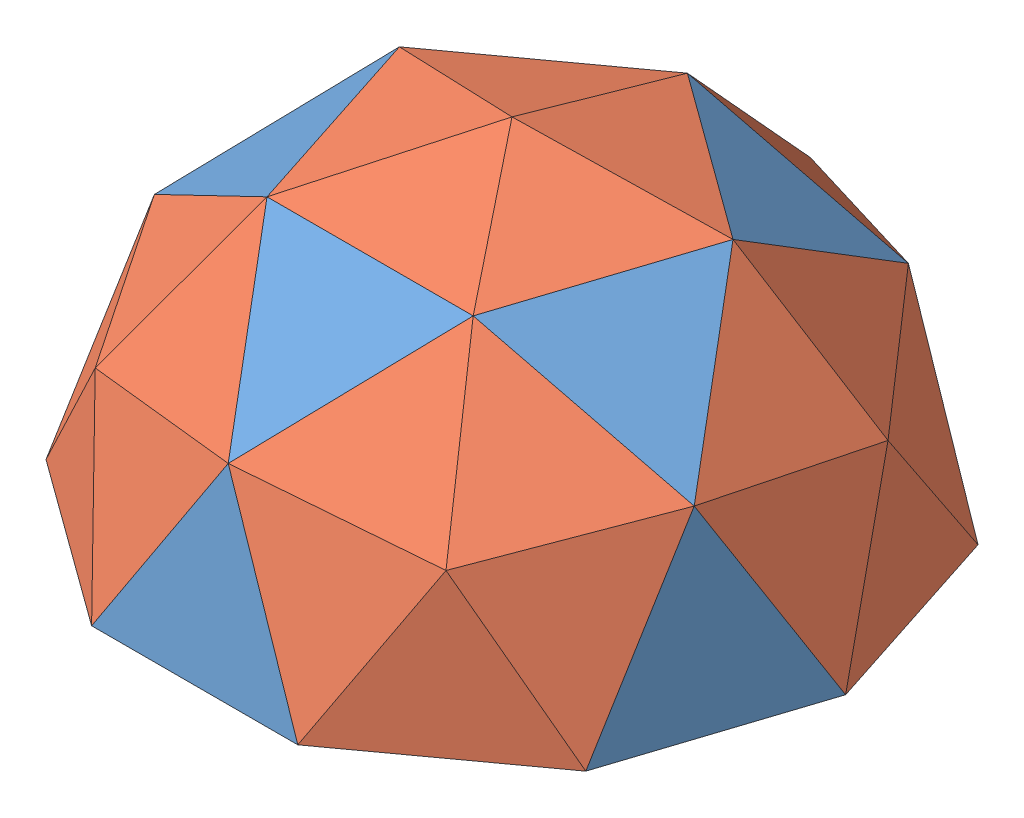
SolidWorks assembly geodome_2V_assembly, configuration Default. Lengths in mm.
Overall size (6090.08 6762.26 6173.15).
40 component instances, 2 part files, 27 mates.
Components (placement in the parent):
- BBB^geodome_2V_assembly_sketch-1: BBB^geodome_2V_assembly_sketch [Default] at (2618.034 525.7311 850.6508) x (0.29759 0.059759 -0.952822) z (0.934172 0.187592 0.303531) size (1850.67 1659.13 10) (virtual)
- BBB^geodome_2V_assembly_sketch-2: BBB^geodome_2V_assembly_sketch [Default] at (1618.034 525.7311 -2227.0327) x (-0.814227 0.059759 -0.577463) z (0.57735 0.187592 -0.794654) size (1850.67 1659.13 10) (virtual)
- BBB^geodome_2V_assembly_sketch-3: BBB^geodome_2V_assembly_sketch [Default] at (-1618.034 525.7311 -2227.0327) x (-0.80081 0.059759 0.59593) z (-0.57735 0.187592 -0.794654) size (1850.67 1659.13 10) (virtual)
- BBB^geodome_2V_assembly_sketch-4: BBB^geodome_2V_assembly_sketch [Default] at (-2618.034 525.7311 850.6508) x (0.319299 0.059759 0.945768) z (-0.934172 0.187592 0.303531) size (1850.67 1659.13 10) (virtual)
- BBB^geodome_2V_assembly_sketch-5: BBB^geodome_2V_assembly_sketch [Default] at (0 525.7311 2752.7638) x (0.998148 0.059759 -0.011413) z (0 0.187592 0.982247) size (1850.67 1659.13 10) (virtual)
- AAB^geodome_2V_assembly_sketch-10: AAB^geodome_2V_assembly_sketch [Default] at (551.221 2670.7024 -758.6906) x (-0.980855 0.187327 -0.053216) z (-0.194739 -0.943522 0.268035) size (1529.28 1639.6 10) (virtual)
- AAB^geodome_2V_assembly_sketch-11: AAB^geodome_2V_assembly_sketch [Default] at (-551.221 2670.7024 -758.6906) x (-0.353712 0.187327 0.916404) z (0.194739 -0.943522 0.268035) size (1529.28 1639.6 10) (virtual)
- AAB^geodome_2V_assembly_sketch-12: AAB^geodome_2V_assembly_sketch [Default] at (-891.8943 2670.7024 289.794) x (0.762249 0.187327 0.619584) z (0.315094 -0.943522 -0.10238) size (1529.28 1639.6 10) (virtual)
- AAB^geodome_2V_assembly_sketch-13: AAB^geodome_2V_assembly_sketch [Default] at (0 2670.7024 937.7931) x (0.824808 0.187327 -0.53348) z (0 -0.943522 -0.331309) size (1529.28 1639.6 10) (virtual)
- AAB^geodome_2V_assembly_sketch-14: AAB^geodome_2V_assembly_sketch [Default] at (891.8943 2670.7024 289.794) x (-0.25249 0.187327 -0.949293) z (-0.315094 -0.943522 -0.10238) size (1529.28 1639.6 10) (virtual)
- BBB^geodome_2V_assembly_sketch-6: BBB^geodome_2V_assembly_sketch [Default] at (1618.034 2227.0327 525.7311) x (0.80081 -0.506291 -0.319958) z (0.57735 0.794654 0.187592) size (1850.67 1659.13 10) (virtual)
- AAB^geodome_2V_assembly_sketch-15: AAB^geodome_2V_assembly_sketch [Default] at (2670.7024 355.5867 -867.7638) x (-0.322433 0.560934 -0.76249) z (-0.943522 -0.125624 0.306569) size (1529.28 1639.6 10) (virtual)
- AAB^geodome_2V_assembly_sketch-16: AAB^geodome_2V_assembly_sketch [Default] at (2670.7024 935.1748 70.0293) x (0.187327 -0.470398 -0.862342) z (-0.943522 -0.330384 -0.02474) size (1529.28 1639.6 10) (virtual)
- AAB^geodome_2V_assembly_sketch-18: AAB^geodome_2V_assembly_sketch [Default] at (2119.4814 1872.9679 -109.0732) x (0.658423 -0.735882 0.15798) z (-0.748783 -0.661694 0.038534) size (1529.28 1639.6 10) (virtual)
- AAB^geodome_2V_assembly_sketch-19: AAB^geodome_2V_assembly_sketch [Default] at (1778.8081 1872.9679 -1157.5578) x (0.439817 0.131372 0.888427) z (-0.628428 -0.661694 0.408949) size (1529.28 1639.6 10) (virtual)
- AAB^geodome_2V_assembly_sketch-20: AAB^geodome_2V_assembly_sketch [Default] at (2119.4814 935.1748 -1626.4544) x (-0.166385 0.932849 0.319545) z (-0.748783 -0.330384 0.574604) size (1529.28 1639.6 10) (virtual)
- BBB^geodome_2V_assembly_sketch-7: BBB^geodome_2V_assembly_sketch [Default] at (1000 2227.0327 -1376.3819) x (-0.056835 -0.506291 -0.860488) z (0.356822 0.794654 -0.491123) size (1850.67 1659.13 10) (virtual)
- BBB^geodome_2V_assembly_sketch-8: BBB^geodome_2V_assembly_sketch [Default] at (-1000 2227.0327 -1376.3819) x (-0.835936 -0.506291 -0.211852) z (-0.356822 0.794654 -0.491123) size (1850.67 1659.13 10) (virtual)
- BBB^geodome_2V_assembly_sketch-9: BBB^geodome_2V_assembly_sketch [Default] at (-1618.034 2227.0327 525.7311) x (-0.459802 -0.506291 0.729556) z (-0.57735 0.794654 0.187592) size (1850.67 1659.13 10) (virtual)
- BBB^geodome_2V_assembly_sketch-10: BBB^geodome_2V_assembly_sketch [Default] at (0 2227.0327 1701.3016) x (0.551762 -0.506291 0.662743) z (0 0.794654 0.607062) size (1850.67 1659.13 10) (virtual)
- AAB^geodome_2V_assembly_sketch-22: AAB^geodome_2V_assembly_sketch [Default] at (551.221 1872.9679 -2049.4521) x (0.353712 -0.735882 -0.577378) z (-0.194739 -0.661694 0.724043) size (1529.28 1639.6 10) (virtual)
- AAB^geodome_2V_assembly_sketch-23: AAB^geodome_2V_assembly_sketch [Default] at (-1778.8081 1872.9679 -1157.5578) x (-0.439817 -0.735882 -0.51482) z (0.628428 -0.661694 0.408949) size (1529.28 1639.6 10) (virtual)
- AAB^geodome_2V_assembly_sketch-24: AAB^geodome_2V_assembly_sketch [Default] at (-1650.5848 1872.9679 1334.042) x (-0.625534 -0.735882 0.259202) z (0.583129 -0.661694 -0.471299) size (1529.28 1639.6 10) (virtual)
- AAB^geodome_2V_assembly_sketch-25: AAB^geodome_2V_assembly_sketch [Default] at (758.6906 1872.9679 1982.0411) x (0.053216 -0.735882 0.675016) z (-0.268035 -0.661694 -0.700228) size (1529.28 1639.6 10) (virtual)
- AAB^geodome_2V_assembly_sketch-26: AAB^geodome_2V_assembly_sketch [Default] at (891.8943 935.1748 -2518.3486) x (-0.762249 -0.470398 -0.444637) z (-0.315094 -0.330384 0.889698) size (1529.28 1639.6 10) (virtual)
- AAB^geodome_2V_assembly_sketch-27: AAB^geodome_2V_assembly_sketch [Default] at (-2119.4814 935.1748 -1626.4544) x (-0.658423 -0.470398 0.587542) z (0.748783 -0.330384 0.574604) size (1529.28 1639.6 10) (virtual)
- AAB^geodome_2V_assembly_sketch-28: AAB^geodome_2V_assembly_sketch [Default] at (-2201.8058 935.1748 1513.1446) x (0.355322 -0.470398 0.807757) z (0.777868 -0.330384 -0.534573) size (1529.28 1639.6 10) (virtual)
- AAB^geodome_2V_assembly_sketch-29: AAB^geodome_2V_assembly_sketch [Default] at (758.6906 935.1748 2561.6291) x (0.878023 -0.470398 -0.08832) z (-0.268035 -0.330384 -0.904988) size (1529.28 1639.6 10) (virtual)
- AAB^geodome_2V_assembly_sketch-30: AAB^geodome_2V_assembly_sketch [Default] at (0 355.5867 -2808.1427) x (-0.824808 0.560934 0.071029) z (0 -0.125624 0.992078) size (1529.28 1639.6 10) (virtual)
- AAB^geodome_2V_assembly_sketch-31: AAB^geodome_2V_assembly_sketch [Default] at (-2670.7024 355.5867 -867.7638) x (-0.187327 0.560934 0.806388) z (0.943522 -0.125624 0.306569) size (1529.28 1639.6 10) (virtual)
- AAB^geodome_2V_assembly_sketch-32: AAB^geodome_2V_assembly_sketch [Default] at (-1650.5848 355.5867 2271.8351) x (0.709034 0.560934 0.427346) z (0.583129 -0.125624 -0.802608) size (1529.28 1639.6 10) (virtual)
- AAB^geodome_2V_assembly_sketch-33: AAB^geodome_2V_assembly_sketch [Default] at (1650.5848 355.5867 2271.8351) x (0.625534 0.560934 -0.542274) z (-0.583129 -0.125624 -0.802608) size (1529.28 1639.6 10) (virtual)
- AAB^geodome_2V_assembly_sketch-34: AAB^geodome_2V_assembly_sketch [Default] at (-891.8943 935.1748 -2518.3486) x (0.25249 0.932849 0.256987) z (0.315094 -0.330384 0.889698) size (1529.28 1639.6 10) (virtual)
- AAB^geodome_2V_assembly_sketch-35: AAB^geodome_2V_assembly_sketch [Default] at (-2670.7024 935.1748 70.0293) x (0.322433 0.932849 -0.160719) z (0.943522 -0.330384 -0.02474) size (1529.28 1639.6 10) (virtual)
- AAB^geodome_2V_assembly_sketch-36: AAB^geodome_2V_assembly_sketch [Default] at (-758.6906 935.1748 2561.6291) x (-0.053216 0.932849 -0.356316) z (0.268035 -0.330384 -0.904988) size (1529.28 1639.6 10) (virtual)
- AAB^geodome_2V_assembly_sketch-37: AAB^geodome_2V_assembly_sketch [Default] at (2201.8058 935.1748 1513.1446) x (-0.355322 0.932849 -0.059497) z (-0.777868 -0.330384 -0.534573) size (1529.28 1639.6 10) (virtual)
- AAB^geodome_2V_assembly_sketch-38: AAB^geodome_2V_assembly_sketch [Default] at (-551.221 1872.9679 -2049.4521) x (0.980855 0.131372 -0.143751) z (0.194739 -0.661694 0.724043) size (1529.28 1639.6 10) (virtual)
- AAB^geodome_2V_assembly_sketch-39: AAB^geodome_2V_assembly_sketch [Default] at (-2119.4814 1872.9679 -109.0732) x (0.166385 0.131372 -0.97727) z (0.748783 -0.661694 0.038534) size (1529.28 1639.6 10) (virtual)
- AAB^geodome_2V_assembly_sketch-40: AAB^geodome_2V_assembly_sketch [Default] at (-758.6906 1872.9679 1982.0411) x (-0.878023 0.131372 -0.460235) z (0.268035 -0.661694 -0.700228) size (1529.28 1639.6 10) (virtual)
- AAB^geodome_2V_assembly_sketch-41: AAB^geodome_2V_assembly_sketch [Default] at (1650.5848 1872.9679 1334.042) x (-0.709034 0.131372 0.692829) z (-0.583129 -0.661694 -0.471299) size (1529.28 1639.6 10) (virtual)
Mates (geometry in assembly coordinates):
- InPlace1: in place: plane of BBB^geodome_2V_assembly_sketch-1 through (2618.034 525.7311 850.6508) normal (0.934172 0.187592 0.303531); moOrthogonalPlaneRef_w of BBB^geodome_2V_assembly_sketch-1 through (2618.034 525.7311 850.6508) normal (-0.196881 0.980427 0); plane of BBB^geodome_2V_assembly_sketch-1 through (2618.034 525.7311 850.6508) normal (0.29759 0.059759 -0.952822); unknown of BBB^geodome_2V_assembly_sketch-1
- Coincident1: coincident: plane of assembly; plane of ?; plane of assembly
- Coincident2: coincident: plane of BBB^geodome_2V_assembly_sketch-1 through (2618.034 525.7311 850.6508) normal (-0.196881 0.980427 0)
- Coincident3: coincident: plane of BBB^geodome_2V_assembly_sketch-1 through (2618.034 525.7311 850.6508) normal (0.29759 0.059759 -0.952822)
- InPlace2: in place: plane of AAB^geodome_2V_assembly_sketch-10 through (551.221 2670.7024 -758.6906) normal (-0.194739 -0.943522 0.268035); plane of AAB^geodome_2V_assembly_sketch-10 through (551.221 2670.7024 -758.6906) normal (0 -0.273267 -0.961938); plane of AAB^geodome_2V_assembly_sketch-10 through (551.221 2670.7024 -758.6906) normal (-0.980855 0.187327 -0.053216); unknown of AAB^geodome_2V_assembly_sketch-10
- Coincident4: coincident: plane of assembly; plane of ?; plane of assembly
- Coincident5: coincident: plane of AAB^geodome_2V_assembly_sketch-10 through (551.221 2670.7024 -758.6906) normal (0 -0.273267 -0.961938)
- Coincident6: coincident: plane of AAB^geodome_2V_assembly_sketch-10 through (551.221 2670.7024 -758.6906) normal (-0.980855 0.187327 -0.053216)
- Coincident7: coincident: unknown of BBB^geodome_2V_assembly_sketch-1; unknown of BBB^geodome_2V_assembly_sketch-6
- Coincident8: coincident: line of BBB^geodome_2V_assembly_sketch-6 through (2427.051 1577.1933 788.5967) axis (-0.5 0.525731 -0.688191)
- Coincident9: coincident: line of AAB^geodome_2V_assembly_sketch-14 through (1500 2551.9524 -487.3795) axis (-0.309017 0 0.951057); line of BBB^geodome_2V_assembly_sketch-6 through (1500 2551.9524 -487.3795) axis (-0.309017 0 0.951057)
- Coincident10: coincident: unknown of AAB^geodome_2V_assembly_sketch-15; unknown of BBB^geodome_2V_assembly_sketch-1
- Coincident16: coincident: unknown of AAB^geodome_2V_assembly_sketch-15
- Coincident17: coincident: unknown of AAB^geodome_2V_assembly_sketch-16
- Coincident18: coincident: unknown of AAB^geodome_2V_assembly_sketch-15; unknown of AAB^geodome_2V_assembly_sketch-16
- Coincident19: coincident: unknown of AAB^geodome_2V_assembly_sketch-15; unknown of AAB^geodome_2V_assembly_sketch-16
- Coincident20: coincident: unknown of BBB^geodome_2V_assembly_sketch-6; unknown of AAB^geodome_2V_assembly_sketch-18
- Coincident21: coincident: unknown of AAB^geodome_2V_assembly_sketch-18
- Coincident22: coincident: unknown of AAB^geodome_2V_assembly_sketch-15; unknown of AAB^geodome_2V_assembly_sketch-18
- Coincident23: coincident: unknown of AAB^geodome_2V_assembly_sketch-15; unknown of AAB^geodome_2V_assembly_sketch-19
- Coincident24: coincident: unknown of BBB^geodome_2V_assembly_sketch-2; unknown of AAB^geodome_2V_assembly_sketch-19
- Coincident25: coincident: unknown of AAB^geodome_2V_assembly_sketch-19
- Coincident26: coincident: unknown of AAB^geodome_2V_assembly_sketch-15; unknown of ?
- Coincident27: coincident: unknown of BBB^geodome_2V_assembly_sketch-2; unknown of ?
- Coincident28: coincident: unknown of BBB^geodome_2V_assembly_sketch-2; unknown of ?
- Coincident30: coincident: unknown of AAB^geodome_2V_assembly_sketch-20; unknown of AAB^geodome_2V_assembly_sketch-22
- Coincident31: coincident: unknown of AAB^geodome_2V_assembly_sketch-20
